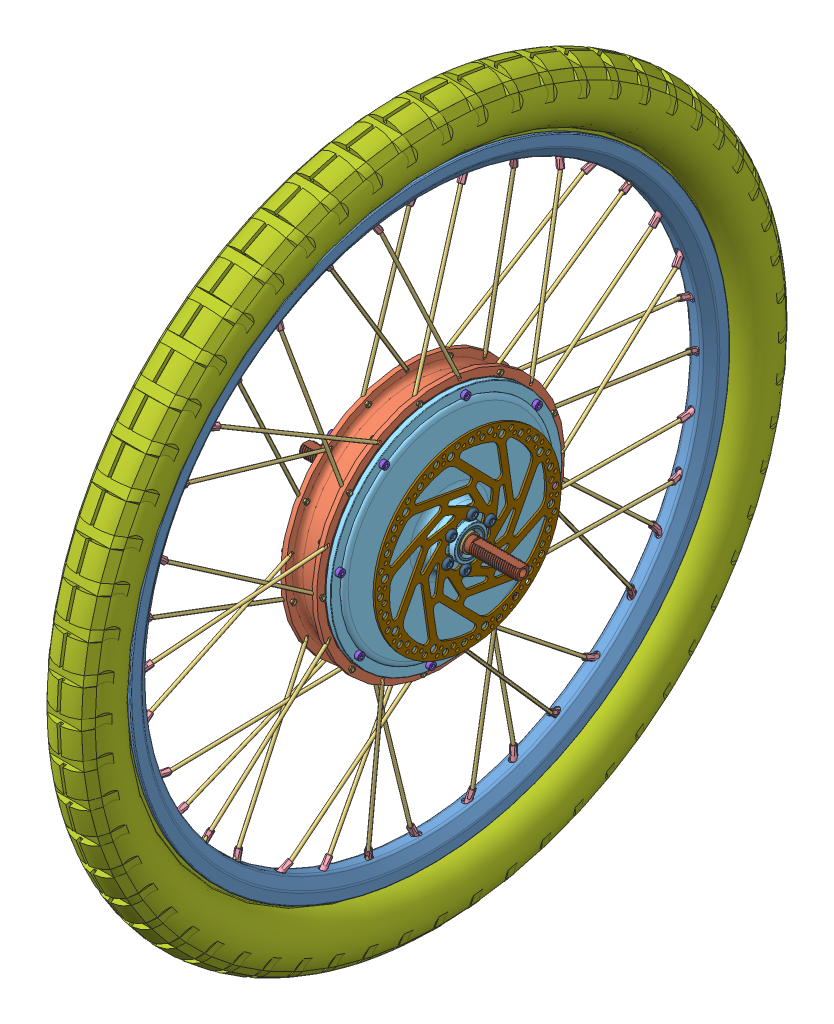
SolidWorks assembly .Rear Wheel eMotor 600W, configuration По умолчанию. Lengths in mm.
Overall size (210 693.38 693.38).
109 component instances, 14 part files, 51 mates.
Components (placement in the parent):
- 26inch rim Vbrake type pistonedHoles-1: .26inch rim Vbrake type pistonedHoles [Default] at (-182.592 -9.6101 580) size (25 580 580)
- 1-Motor Rotor-2: .1-Motor Rotor [По умолчанию] at (-160.092 -9.6101 580) x (0 0.158861 0.987301) z (-1 0 0) size (240 240 36)
- Spoke D3x160-1: .Spoke D3x160 [По умолчанию<Как обработанный>] at (-171.5597 190.5092 596.4307) x (-0.122581 0.920198 0.371764) z (0 -0.374589 0.927191) size (185.5 8.8 5)
- Nut Spokes-1: .Nut Spokes [По умолчанию] at (-182.592 259.5564 627.4613) x (0.418711 0.580778 -0.698124) z (0.230429 -0.811546 -0.536932) size (9 9 15)
- Spoke D3x160-2: .Spoke D3x160 [По умолчанию<Как обработанный>] at (-173.7181 188.552 565.6467) x (-0.0986 0.915447 -0.390174) z (0 -0.392084 -0.919929) size (185.5 8.8 5)
- Nut Spokes-64: .Nut Spokes [По умолчанию] at (-182.592 259.7657 532.5018) x (0.529386 -0.384429 -0.756283) z (0.169202 -0.825691 0.538149) size (9 9 15)
- Spoke D3x160-3: .Spoke D3x160 [По умолчанию<Как обработанный>] at (-186.5307 184.5302 630.8194) x (0.043763 0.847529 0.528941) z (0 -0.529449 0.848342) size (185.5 8.8 5)
- Nut Spokes-65: .Nut Spokes [По умолчанию] at (-182.592 247.5493 673.5984) x (0.485279 0.569067 -0.663828) z (-0.083126 -0.72575 -0.682918) size (9 9 15)
- Spoke D3x160-4: .Spoke D3x160 [По умолчанию<Как обработанный>] at (-188.7293 189.0251 600.1922) x (0.068192 0.972118 -0.224358) z (0 -0.224882 -0.974386) size (185.5 8.8 5)
- Nut Spokes-66: .Nut Spokes [По умолчанию] at (-182.592 263.92 580) x (0.504642 -0.40671 -0.761527) z (-0.122533 -0.906895 0.403147) size (9 9 15)
- Nut Spokes-67: .Nut Spokes [По умолчанию] at (-182.592 166.2124 370.4629) x (0.529386 -0.78062 -0.33224) z (0.169202 -0.2866 0.94299) size (9 9 15)
- Nut Spokes-68: .Nut Spokes [По умолчанию] at (-182.592 -9.6101 306.4687) x (0.529386 -0.811549 0.247262) z (0.169202 0.386594 0.906596) size (9 9 15)
- Nut Spokes-69: .Nut Spokes [По умолчанию] at (-182.592 -185.4326 370.4629) x (0.529386 -0.462746 0.711067) z (0.169202 0.878897 0.445995) size (9 9 15)
- Nut Spokes-70: .Nut Spokes [По умолчанию] at (-182.592 -278.9859 532.5018) x (0.529386 0.102581 0.842157) z (0.169202 0.959954 -0.223292) size (9 9 15)
- Nut Spokes-71: .Nut Spokes [По умолчанию] at (-182.592 -246.4952 716.7657) x (0.529386 0.61991 0.579191) z (0.169202 0.591838 -0.788098) size (9 9 15)
- Nut Spokes-72: .Nut Spokes [По умолчанию] at (-182.592 -103.1633 837.0354) x (0.529386 0.847175 0.045216) z (0.169202 -0.053205 -0.984144) size (9 9 15)
- Nut Spokes-73: .Nut Spokes [По умолчанию] at (-182.592 83.9431 837.0354) x (0.529386 0.678038 -0.509916) z (0.169202 -0.673353 -0.719698) size (9 9 15)
- Nut Spokes-74: .Nut Spokes [По умолчанию] at (-182.592 227.275 716.7657) x (0.529386 0.19164 -0.826453) z (0.169202 -0.978432 -0.118498) size (9 9 15)
- Spoke D3x160-5: .Spoke D3x160 [По умолчанию<Как обработанный>] at (-173.7181 132.9648 441.6286) x (-0.0986 0.450474 -0.887328) z (0 -0.891673 -0.45268) size (185.5 8.8 5)
- Spoke D3x160-6: .Spoke D3x160 [По умолчанию<Как обработанный>] at (-173.7181 10.6652 382.356) x (-0.0986 -0.225281 -0.969292) z (0 -0.974038 0.226384) size (185.5 8.8 5)
- Spoke D3x160-7: .Spoke D3x160 [По умолчанию<Как обработанный>] at (-173.7181 -121.1215 415.5632) x (-0.0986 -0.795624 -0.597713) z (0 -0.60064 0.79952) size (185.5 8.8 5)
- Spoke D3x160-8: .Spoke D3x160 [По умолчанию<Как обработанный>] at (-173.7181 -200.7307 525.7122) x (-0.0986 -0.993686 0.053542) z (0 0.053805 0.998551) size (185.5 8.8 5)
- Spoke D3x160-9: .Spoke D3x160 [По умолчанию<Как обработанный>] at (-173.7181 -190.9125 661.2631) x (-0.0986 -0.726791 0.679745) z (0 0.683073 0.73035) size (185.5 8.8 5)
- Spoke D3x160-10: .Spoke D3x160 [По умолчанию<Как обработанный>] at (-173.7181 -96.2608 758.7901) x (-0.0986 -0.119823 0.987887) z (0 0.992724 0.120409) size (185.5 8.8 5)
- Spoke D3x160-11: .Spoke D3x160 [По умолчанию<Как обработанный>] at (-173.7181 38.9356 772.6592) x (-0.0986 0.543212 0.833786) z (0 0.837869 -0.545872) size (185.5 8.8 5)
- Spoke D3x160-12: .Spoke D3x160 [По умолчанию<Как обработанный>] at (-173.7181 151.417 696.3809) x (-0.0986 0.952072 0.289547) z (0 0.290965 -0.956734) size (185.5 8.8 5)
- Nut Spokes-75: .Nut Spokes [По умолчанию] at (-182.592 227.0909 443.3406) x (0.418711 -0.003844 -0.908111) z (0.230429 -0.966813 0.110338) size (9 9 15)
- Nut Spokes-76: .Nut Spokes [По умолчанию] at (-182.592 83.8704 323.1643) x (0.418711 -0.586667 -0.693183) z (0.230429 -0.669698 0.705979) size (9 9 15)
- Nut Spokes-77: .Nut Spokes [По умолчанию] at (-182.592 -103.0906 323.1643) x (0.418711 -0.894983 -0.153907) z (0.230429 -0.059224 0.971285) size (9 9 15)
- Nut Spokes-78: .Nut Spokes [По умолчанию] at (-182.592 -246.3111 443.3406) x (0.418711 -0.784526 0.457384) z (0.230429 0.578962 0.782116) size (9 9 15)
- Nut Spokes-79: .Nut Spokes [По умолчанию] at (-182.592 -278.7766 627.4613) x (0.418711 -0.306981 0.85466) z (0.230429 0.946245 0.226986) size (9 9 15)
- Nut Spokes-80: .Nut Spokes [По умолчанию] at (-182.592 -185.2961 789.3744) x (0.418711 0.314204 0.852031) z (0.230429 0.87077 -0.434353) size (9 9 15)
- Nut Spokes-81: .Nut Spokes [По умолчанию] at (-182.592 -9.6101 853.3188) x (0.418711 0.788369 0.450727) z (0.230429 0.387851 -0.892454) size (9 9 15)
- Nut Spokes-82: .Nut Spokes [По умолчанию] at (-182.592 166.0758 789.3744) x (0.418711 0.893648 -0.161477) z (0.230429 -0.276547 -0.932965) size (9 9 15)
- Spoke D3x160-13: .Spoke D3x160 [По умолчанию<Как обработанный>] at (-171.5597 154.2516 463.9524) x (-0.122581 0.943878 -0.306704) z (0 0.309035 0.951051) size (185.5 8.8 5)
- Spoke D3x160-14: .Spoke D3x160 [По умолчанию<Как обработанный>] at (-171.5597 41.3213 385.7741) x (-0.122581 0.525907 -0.841662) z (0 0.848058 0.529903) size (185.5 8.8 5)
- Spoke D3x160-15: .Spoke D3x160 [По умолчанию<Как обработанный>] at (-171.5597 -95.4404 398.4762) x (-0.122581 -0.138142 -0.982797) z (0 0.990265 -0.139192) size (185.5 8.8 5)
- Spoke D3x160-16: .Spoke D3x160 [По умолчанию<Как обработанный>] at (-171.5597 -192.0411 496.1154) x (-0.122581 -0.737553 -0.66407) z (0 0.669117 -0.743157) size (185.5 8.8 5)
- Spoke D3x160-17: .Spoke D3x160 [По умолчанию<Как обработанный>] at (-171.5597 -203.2804 633.005) x (-0.122581 -0.991855 -0.034618) z (0 0.034881 -0.999391) size (185.5 8.8 5)
- Spoke D3x160-18: .Spoke D3x160 [По умолчанию<Как обработанный>] at (-171.5597 -123.8992 745.0931) x (-0.122581 -0.782056 0.611033) z (0 -0.615676 -0.787999) size (185.5 8.8 5)
- Spoke D3x160-19: .Spoke D3x160 [По умолчанию<Как обработанный>] at (-171.5597 8.9592 779.9322) x (-0.122581 -0.206325 0.970775) z (0 -0.978152 -0.207893) size (185.5 8.8 5)
- Spoke D3x160-20: .Spoke D3x160 [По умолчанию<Как обработанный>] at (-171.5597 133.1287 721.2209) x (-0.122581 0.465948 0.87628) z (0 -0.882939 0.469488) size (185.5 8.8 5)
- Nut Spokes-83: .Nut Spokes [По умолчанию] at (-182.592 247.5493 486.4016) x (0.485279 0.00923 -0.874311) z (-0.083126 -0.994928 -0.056642) size (9 9 15)
- Nut Spokes-84: .Nut Spokes [По умолчанию] at (-182.592 127.2216 343.0006) x (0.485279 -0.554925 -0.675694) z (-0.083126 -0.798568 0.596137) size (9 9 15)
- Nut Spokes-85: .Nut Spokes [По умолчанию] at (-182.592 -57.1312 310.4942) x (0.485279 -0.859425 -0.160912) z (-0.083126 -0.228549 0.969977) size (9 9 15)
- Nut Spokes-86: .Nut Spokes [По умолчанию] at (-182.592 -219.2484 404.0926) x (0.485279 -0.761791 0.429162) z (-0.083126 0.448411 0.889954) size (9 9 15)
- Nut Spokes-87: .Nut Spokes [По умолчанию] at (-182.592 -283.2734 580) x (0.485279 -0.307705 0.818427) z (-0.083126 0.915554 0.393511) size (9 9 15)
- Nut Spokes-88: .Nut Spokes [По умолчанию] at (-182.592 -219.2484 755.9074) x (0.485279 0.290358 0.82474) z (-0.083126 0.954299 -0.28706) size (9 9 15)
- Nut Spokes-89: .Nut Spokes [По умолчанию] at (-182.592 -57.1312 849.5058) x (0.485279 0.75256 0.445149) z (-0.083126 0.546517 -0.833312) size (9 9 15)
- Nut Spokes-90: .Nut Spokes [По умолчанию] at (-182.592 127.2216 816.9994) x (0.485279 0.862631 -0.142733) z (-0.083126 -0.116986 -0.989649) size (9 9 15)
- Spoke D3x160-21: .Spoke D3x160 [По умолчанию<Как обработанный>] at (-186.5307 171.7761 494.1389) x (0.043763 0.989242 -0.139589) z (0 0.139722 0.990191) size (185.5 8.8 5)
- Spoke D3x160-22: .Spoke D3x160 [По умолчанию<Как обработанный>] at (-186.5307 74.1493 397.6338) x (0.043763 0.668078 -0.742804) z (0 0.743516 0.668718) size (185.5 8.8 5)
- Spoke D3x160-23: .Spoke D3x160 [По умолчанию<Как обработанный>] at (-186.5307 -62.6694 386.4599) x (0.043763 0.034312 -0.998453) z (0 0.99941 0.034345) size (185.5 8.8 5)
- Spoke D3x160-24: .Spoke D3x160 [По умолчанию<Как обработанный>] at (-186.5307 -174.6611 465.8455) x (0.043763 -0.615508 -0.786914) z (0 0.787669 -0.616099) size (185.5 8.8 5)
- Spoke D3x160-25: .Spoke D3x160 [По умолчанию<Как обработанный>] at (-186.5307 -209.4236 598.6453) x (0.043763 -0.977326 -0.20717) z (0 0.207369 -0.978263) size (185.5 8.8 5)
- Spoke D3x160-26: .Spoke D3x160 [По умолчанию<Как обработанный>] at (-186.5307 -150.6911 722.7208) x (0.043763 -0.881841 0.469511) z (0 -0.469961 -0.882687) size (185.5 8.8 5)
- Spoke D3x160-27: .Spoke D3x160 [По умолчанию<Как обработанный>] at (-186.5307 -25.9453 780.0156) x (0.043763 -0.373734 0.926503) z (0 -0.927392 -0.374092) size (185.5 8.8 5)
- Spoke D3x160-28: .Spoke D3x160 [По умолчанию<Как обработанный>] at (-186.5307 106.444 743.7209) x (0.043763 0.309248 0.949974) z (0 -0.950885 0.309545) size (185.5 8.8 5)
- Nut Spokes-91: .Nut Spokes [По умолчанию] at (-182.592 199.9261 404.1782) x (0.504642 -0.801058 -0.321936) z (-0.122533 -0.435584 0.891769) size (9 9 15)
- Nut Spokes-92: .Nut Spokes [По умолчанию] at (-182.592 37.8879 310.6254) x (0.504642 -0.820582 0.268293) z (-0.122533 0.239542 0.963123) size (9 9 15)
- Nut Spokes-93: .Nut Spokes [По умолчанию] at (-182.592 -146.3752 343.1159) x (0.504642 -0.456147 0.732984) z (-0.122533 0.802583 0.58382) size (9 9 15)
- Nut Spokes-94: .Nut Spokes [По умолчанию] at (-182.592 -266.6444 486.4472) x (0.504642 0.121724 0.854704) z (-0.122533 0.990087 -0.068658) size (9 9 15)
- Nut Spokes-95: .Nut Spokes [По умолчанию] at (-182.592 -266.6444 673.5528) x (0.504642 0.64264 0.576499) z (-0.122533 0.714318 -0.689011) size (9 9 15)
- Nut Spokes-96: .Nut Spokes [По умолчанию] at (-182.592 -146.3752 816.8841) x (0.504642 0.862857 0.028543) z (-0.122533 0.104312 -0.986967) size (9 9 15)
- Nut Spokes-97: .Nut Spokes [По умолчанию] at (-182.592 37.8879 849.3746) x (0.504642 0.679333 -0.532769) z (-0.122533 -0.554503 -0.823111) size (9 9 15)
- Nut Spokes-98: .Nut Spokes [По умолчанию] at (-182.592 199.9261 755.8218) x (0.504642 0.177943 -0.844791) z (-0.122533 -0.95386 -0.274112) size (9 9 15)
- Spoke D3x160-29: .Spoke D3x160 [По умолчанию<Как обработанный>] at (-188.7293 155.5326 467.7879) x (0.068192 0.600471 -0.796734) z (0 -0.798593 -0.601872) size (185.5 8.8 5)
- Spoke D3x160-30: .Spoke D3x160 [По умолчанию<Как обработанный>] at (-188.7293 44.768 387.8889) x (0.068192 -0.052143 -0.996309) z (0 -0.998633 0.052265) size (185.5 8.8 5)
- Spoke D3x160-31: .Spoke D3x160 [По умолчанию<Как обработанный>] at (-188.7293 -91.4407 397.8808) x (0.068192 -0.680359 -0.7297) z (0 -0.731402 0.681946) size (185.5 8.8 5)
- Spoke D3x160-32: .Spoke D3x160 [По умолчанию<Как обработанный>] at (-188.7293 -189.36 493.0883) x (0.068192 -0.990227 -0.121656) z (0 -0.12194 0.992537) size (185.5 8.8 5)
- Spoke D3x160-33: .Spoke D3x160 [По умолчанию<Как обработанный>] at (-188.7293 -203.1723 628.9627) x (0.068192 -0.836757 0.543312) z (0 0.544579 0.838709) size (185.5 8.8 5)
- Spoke D3x160-34: .Spoke D3x160 [По умолчанию<Как обработанный>] at (-188.7293 -126.4147 741.927) x (0.068192 -0.291759 0.954058) z (0 0.956284 0.29244) size (185.5 8.8 5)
- Spoke D3x160-35: .Spoke D3x160 [По умолчанию<Как обработанный>] at (-188.7293 4.9971 779.1238) x (0.068192 0.389756 0.91839) z (0 0.920533 -0.390666) size (185.5 8.8 5)
- Spoke D3x160-36: .Spoke D3x160 [По умолчанию<Как обработанный>] at (-188.7293 129.574 723.1484) x (0.068192 0.8889 0.452997) z (0 0.454054 -0.890974) size (185.5 8.8 5)
- 2-Motor Shield RotorBrakeSide-1: .2-Motor Shield RotorBrakeSide [По умолчанию] at (-159.592 -9.6101 580) x (0 -0.158861 -0.987301) z (1 0 0) size (224 224 29)
- 2-Motor Shield Rear Wheel RigtSide Cassette-1: .2-Motor Shield Rear Wheel RigtSide Cassette [По умолчанию] at (-195.592 -9.6101 580) x (0 0.810459 0.585795) z (-1 0 0) size (224 224 41)
- Wheel Gum-1: .Wheel Gum [По умолчанию] at (-183.092 -9.6101 580) size (55 693.38 693.38)
- M4x10 8.8-1: .M4x10 8.8 [По умолчанию] at (-204.492 7.2292 684.6539) x (0 0.438024 -0.898963) z (1 0 0) size (6.9 6.9 14.35)
- M4x10 8.8-2: .M4x10 8.8 [По умолчанию] at (-204.492 76.2985 642.0943) x (0 -0.325933 -0.945393) z (1 0 0) size (6.9 6.9 14.35)
- M4x10 8.8-3: .M4x10 8.8 [По умолчанию] at (-204.492 95.0438 563.1607) x (0 -0.898963 -0.438024) z (1 0 0) size (6.9 6.9 14.35)
- M4x10 8.8-4: .M4x10 8.8 [По умолчанию] at (-204.492 52.4842 494.0914) x (0 -0.945393 0.325933) z (1 0 0) size (6.9 6.9 14.35)
- M4x10 8.8-5: .M4x10 8.8 [По умолчанию] at (-204.492 -26.4494 475.3461) x (0 -0.438024 0.898963) z (1 0 0) size (6.9 6.9 14.35)
- M4x10 8.8-6: .M4x10 8.8 [По умолчанию] at (-204.492 -95.5188 517.9057) x (0 0.325933 0.945393) z (1 0 0) size (6.9 6.9 14.35)
- M4x10 8.8-7: .M4x10 8.8 [По умолчанию] at (-204.492 -114.264 596.8393) x (0 0.898963 0.438024) z (1 0 0) size (6.9 6.9 14.35)
- M4x10 8.8-8: .M4x10 8.8 [По умолчанию] at (-204.492 -71.7044 665.9086) x (0 0.945393 -0.325933) z (1 0 0) size (6.9 6.9 14.35)
- M4x10 8.8-9: .M4x10 8.8 [По умолчанию] at (-150.692 -95.5188 517.9057) x (0 0.110879 0.993834) z (-1 0 0) size (6.9 6.9 14.35)
- M4x10 8.8-10: .M4x10 8.8 [По умолчанию] at (-150.692 -26.4494 475.3461) x (0 -0.624343 0.78115) z (-1 0 0) size (6.9 6.9 14.35)
- M4x10 8.8-11: .M4x10 8.8 [По умолчанию] at (-150.692 52.4842 494.0914) x (0 -0.993834 0.110879) z (-1 0 0) size (6.9 6.9 14.35)
- M4x10 8.8-12: .M4x10 8.8 [По умолчанию] at (-150.692 95.0438 563.1607) x (0 -0.78115 -0.624343) z (-1 0 0) size (6.9 6.9 14.35)
- M4x10 8.8-13: .M4x10 8.8 [По умолчанию] at (-150.692 76.2985 642.0943) x (0 -0.110879 -0.993834) z (-1 0 0) size (6.9 6.9 14.35)
- M4x10 8.8-14: .M4x10 8.8 [По умолчанию] at (-150.692 7.2292 684.6539) x (0 0.624343 -0.78115) z (-1 0 0) size (6.9 6.9 14.35)
- M4x10 8.8-15: .M4x10 8.8 [По умолчанию] at (-150.692 -71.7044 665.9086) x (0 0.993834 -0.110879) z (-1 0 0) size (6.9 6.9 14.35)
- M4x10 8.8-16: .M4x10 8.8 [По умолчанию] at (-150.692 -114.264 596.8393) x (0 0.78115 0.624343) z (-1 0 0) size (6.9 6.9 14.35)
- Rotor Disk Brake 180mm-1: .Rotor Disk Brake 180mm [Default] at (-133.692 -9.6101 580) x (0 0.631228 0.775597) z (-1 0 0) size (180 180 1.9)
- M6x20 8.8 rounded head-1: .M6x20 8.8 rounded head [По умолчанию] at (-130.692 4.2769 597.0631) x (0 0 1) z (-1 0 0) size (9.9 9.9 23.58)
- M6x20 8.8 rounded head-2: .M6x20 8.8 rounded head [По умолчанию] at (-130.692 -17.4437 600.5581) x (0 -0.866025 0.5) z (-1 0 0) size (9.9 9.9 23.58)
- M6x20 8.8 rounded head-3: .M6x20 8.8 rounded head [По умолчанию] at (-130.692 -31.3307 583.4949) x (0 -0.866025 -0.5) z (-1 0 0) size (9.9 9.9 23.58)
- M6x20 8.8 rounded head-4: .M6x20 8.8 rounded head [По умолчанию] at (-130.692 -23.4971 562.9369) x (0 0 -1) z (-1 0 0) size (9.9 9.9 23.58)
- M6x20 8.8 rounded head-5: .M6x20 8.8 rounded head [По умолчанию] at (-130.692 -1.7765 559.4419) x (0 0.866025 -0.5) z (-1 0 0) size (9.9 9.9 23.58)
- M6x20 8.8 rounded head-6: .M6x20 8.8 rounded head [По умолчанию] at (-130.692 12.1105 576.5051) x (0 0.866025 0.5) z (-1 0 0) size (9.9 9.9 23.58)
- shaft rear 14mm-1: .shaft rear 14mm [По умолчанию] at (-80.592 -9.6101 580) x (0 0.052208 0.998636) z (-1 0 0) size (16.17 14 210)
- 26x14x8 rolled-1: .26x14x8 rolled [По умолчанию] at (-151.592 -8.9482 574.9476) x (0 0.494808 -0.869002) z (1 0 0) size (28.13 28.13 8)
  - InnerCage-1: .InnerCage [По умолчанию] at (-4.7181 1.9248 13) size (17 17 8)
  - roll 3mm-1: .roll 3mm [По умолчанию] at (-14.7166 2.0947 13.75) size (3 3 6.5)
  - Outter Cage-1: .Outter Cage [По умолчанию] at (-4.7181 1.9248 13) x (0.085785 -0.996314 0) z (0 0 1) size (26 26 8)
- 26x14x8 rolled-2: .26x14x8 rolled [По умолчанию] at (-249.592 -11.5349 575.2819) x (0 0 -1) z (1 0 0) size (28.13 28.13 8)
  - InnerCage-1: .InnerCage [По умолчанию] at (-4.7181 1.9248 13) size (17 17 8)
  - roll 3mm-1: .roll 3mm [По умолчанию] at (-14.7166 2.0947 13.75) size (3 3 6.5)
  - Outter Cage-1: .Outter Cage [По умолчанию] at (-4.7181 1.9248 13) x (0.085785 -0.996314 0) z (0 0 1) size (26 26 8)
Mates (geometry in assembly coordinates):
- Расстояние1: distance = 0 mm aligned: plane of 1-Motor Rotor-2 through (-195.092 -9.6101 580) normal (-1 0 0); plane of 26inch rim Vbrake type pistonedHoles-1 through (-195.092 -298.6101 580) normal (-1 0 0)
- Концентричный1: concentric anti-aligned: cylinder of 26inch rim Vbrake type pistonedHoles-1 through (-198.7674 -9.6101 580) axis (-1 0 0) radius 269; cylinder of 1-Motor Rotor-2 through (-160.092 -9.6101 580) axis (1 0 0) radius 108
- Совпадение1: coincident: line of assembly; point of Spoke D3x160-1; line of 26inch rim Vbrake type pistonedHoles-1 through (-182.592 275.9841 630.358) axis (0 -0.984808 -0.173648)
- Совпадение2: coincident: line of assembly; point of 1-Motor Rotor-2; line of Spoke D3x160-1 through (-160.5274 107.6913 562.9719) axis (-0.122581 0.920198 0.371764)
- Совпадение3: coincident: line of assembly; point of 1-Motor Rotor-2; line of Spoke D3x160-1 through (-163.137 104.5898 561.7189) axis (-0.992458 -0.113656 -0.045918)
- Совпадение4: coincident: line of Spoke D3x160-1 through (-160.5274 107.6913 562.9719) axis (-0.122581 0.920198 0.371764)
- Совпадение5: coincident: line of 26inch rim Vbrake type pistonedHoles-1 through (-182.592 275.9841 630.358) axis (0 -0.984808 -0.173648)
- Совпадение6: coincident: line of Spoke D3x160-1 through (-160.5274 107.6913 562.9719) axis (-0.122581 0.920198 0.371764)
- Совпадение7: coincident: line of 26inch rim Vbrake type pistonedHoles-1 through (-182.592 275.9841 630.358) axis (0 -0.984808 -0.173648)
- Расстояние3: distance = 9 mm: cylinder of assembly; point of Nut Spokes-1; cylinder of 26inch rim Vbrake type pistonedHoles-1 through (-198.7674 -9.6101 580) axis (-1 0 0) radius 269
- Совпадение9: coincident: line of 26inch rim Vbrake type pistonedHoles-1 through (-182.592 275.9841 529.642) axis (0 -0.984808 0.173648)
- Совпадение11: coincident: line of assembly; point of 1-Motor Rotor-2; line of Spoke D3x160-2 through (-164.8441 106.1618 600.7624) axis (-0.0986 0.915447 -0.390174)
- Совпадение12: coincident: line of assembly; point of 1-Motor Rotor-2; line of Spoke D3x160-2 through (-161.5629 103.6876 601.8169) axis (0.995127 0.090705 -0.038659)
- Совпадение13: coincident: line of 26inch rim Vbrake type pistonedHoles-1 through (-182.592 275.9841 529.642) axis (0 -0.984808 0.173648)
- Совпадение14: coincident: line of Spoke D3x160-2 through (-164.8441 106.1618 600.7624) axis (-0.0986 0.915447 -0.390174)
- Расстояние4: distance = 9 mm: cylinder of assembly; point of Nut Spokes-64; cylinder of 26inch rim Vbrake type pistonedHoles-1 through (-198.7674 -9.6101 580) axis (-1 0 0) radius 269
- Совпадение16: coincident: line of 26inch rim Vbrake type pistonedHoles-1 through (-182.592 262.9008 679.1858) axis (0 -0.939693 -0.34202)
- Совпадение17: coincident: line of assembly; point of 1-Motor Rotor-2; line of Spoke D3x160-3 through (-190.4694 108.2526 583.2146) axis (0.043763 0.847529 0.528941)
- Совпадение18: coincident: line of assembly; point of 1-Motor Rotor-2; line of Spoke D3x160-3 through (-193.5978 105.8214 581.6973) axis (-0.999042 0.037126 0.02317)
- Совпадение19: coincident: line of 26inch rim Vbrake type pistonedHoles-1 through (-182.592 262.9008 679.1858) axis (0 -0.939693 -0.34202)
- Совпадение20: coincident: line of Spoke D3x160-3 through (-190.4694 108.2526 583.2146) axis (0.043763 0.847529 0.528941)
- Расстояние5: distance = 9 mm: cylinder of assembly; point of Nut Spokes-65; cylinder of 26inch rim Vbrake type pistonedHoles-1 through (-198.7674 -9.6101 580) axis (-1 0 0) radius 269
- Совпадение21: coincident: line of 26inch rim Vbrake type pistonedHoles-1 through (-182.592 280.3899 580) axis (0 -1 0)
- Совпадение22: coincident: line of assembly; point of 1-Motor Rotor-2; line of Spoke D3x160-4 through (-194.8665 101.5345 620.3845) axis (0.068192 0.972118 -0.224358)
- Совпадение23: coincident: line of assembly; point of 1-Motor Rotor-2; line of Spoke D3x160-4 through (-192.0781 98.4188 621.1036) axis (0.997672 -0.066445 0.015335)
- Совпадение24: coincident: line of 26inch rim Vbrake type pistonedHoles-1 through (-182.592 280.3899 580) axis (0 -1 0)
- Совпадение25: coincident: line of Spoke D3x160-4 through (-194.8665 101.5345 620.3845) axis (0.068192 0.972118 -0.224358)
- Расстояние6: distance = 9 mm: cylinder of assembly; point of Nut Spokes-66; cylinder of 26inch rim Vbrake type pistonedHoles-1 through (-198.7674 -9.6101 580) axis (-1 0 0) radius 269
- Расстояние7: distance = 0 mm anti-aligned: plane of 2-Motor Shield RotorBrakeSide-1 through (-159.592 -9.6101 580) normal (-1 0 0); plane of 1-Motor Rotor-2 through (-159.592 -9.6101 580) normal (1 0 0)
- Концентричный3: concentric anti-aligned: cylinder of 1-Motor Rotor-2 through (-159.592 -9.6101 580) axis (-1 0 0) radius 100; cylinder of 2-Motor Shield RotorBrakeSide-1 through (-159.592 -9.6101 580) axis (1 0 0) radius 7.25
- Концентричный4: concentric aligned: cylinder of 1-Motor Rotor-2 through (-165.592 52.4842 494.0914) axis (1 0 0) radius 1.6; circle of 2-Motor Shield RotorBrakeSide-1
- Концентричный5: concentric aligned: cylinder of 1-Motor Rotor-2 through (-159.592 -9.6101 580) axis (-1 0 0) radius 100; cylinder of 2-Motor Shield Rear Wheel RigtSide Cassette-1 through (-195.592 -9.6101 580) axis (-1 0 0) radius 7.25
- Расстояние8: distance = 0 mm anti-aligned: plane of 2-Motor Shield Rear Wheel RigtSide Cassette-1 through (-195.592 -9.6101 580) normal (1 0 0); plane of 1-Motor Rotor-2 through (-195.592 -9.6101 580) normal (-1 0 0)
- Концентричный6: concentric aligned: circle of 1-Motor Rotor-2; circle of 2-Motor Shield Rear Wheel RigtSide Cassette-1
- Совпадение27: coincident anti-aligned: plane of 26inch rim Vbrake type pistonedHoles-1 through (-191.092 -298.6101 580) normal (1 0 0); plane of Wheel Gum-1 through (-191.092 282.608 580) normal (-1 0 0)
- Концентричный7: concentric aligned: cylinder of 26inch rim Vbrake type pistonedHoles-1 through (-198.7674 -9.6101 580) axis (-1 0 0) radius 282; circle of Wheel Gum-1
- Расстояние9: distance = 0 mm anti-aligned: plane of M4x10 8.8-1 through (-200.592 7.2292 684.6539) normal (1 0 0); plane of 2-Motor Shield Rear Wheel RigtSide Cassette-1 through (-200.592 -9.6101 580) normal (-1 0 0)
- Концентричный8: concentric aligned: circle of 2-Motor Shield Rear Wheel RigtSide Cassette-1; cylinder of M4x10 8.8-1 through (-200.592 7.2292 684.6539) axis (-1 0 0) radius 3.45
- Расстояние10: distance = 0 mm anti-aligned: plane of M4x10 8.8-9 through (-154.592 -95.5188 517.9057) normal (-1 0 0); plane of 2-Motor Shield RotorBrakeSide-1 through (-154.592 -9.6101 580) normal (1 0 0)
- Концентричный9: concentric aligned: circle of 2-Motor Shield RotorBrakeSide-1; cylinder of M4x10 8.8-9 through (-154.592 -95.5188 517.9057) axis (1 0 0) radius 3.45
- Расстояние11: distance = 1 mm anti-aligned: plane of 2-Motor Shield RotorBrakeSide-1 through (-136.592 -9.6101 580) normal (1 0 0); plane of Rotor Disk Brake 180mm-1 through (-135.592 -9.6101 580) normal (-1 0 0)
- Концентричный10: concentric anti-aligned: cylinder of 2-Motor Shield RotorBrakeSide-1 through (-159.592 -9.6101 580) axis (1 0 0) radius 7.25; circle of Rotor Disk Brake 180mm-1
- Концентричный11: concentric aligned: circle of 2-Motor Shield RotorBrakeSide-1; circle of Rotor Disk Brake 180mm-1
- Расстояние12: distance = 0 mm anti-aligned: plane of M6x20 8.8 rounded head-1 through (-133.692 4.2769 597.0631) normal (-1 0 0); plane of Rotor Disk Brake 180mm-1 through (-133.692 -9.6101 580) normal (1 0 0)
- Концентричный12: concentric aligned: circle of Rotor Disk Brake 180mm-1; cylinder of M6x20 8.8 rounded head-1 through (-133.692 4.2769 597.0631) axis (1 0 0) radius 4.95
- Концентричный13: concentric aligned: cylinder of 2-Motor Shield RotorBrakeSide-1 through (-159.592 -9.6101 580) axis (1 0 0) radius 7.25; cylinder of shaft rear 14mm-1 through (-290.592 -9.6101 580) axis (1 0 0) radius 7
- Расстояние13: distance = 50 mm aligned: plane of 2-Motor Shield RotorBrakeSide-1 through (-130.592 -9.6101 580) normal (1 0 0); plane of shaft rear 14mm-1 through (-80.592 -9.6101 580) normal (1 0 0)
- Концентричный14: concentric aligned: cylinder of 2-Motor Shield RotorBrakeSide-1 through (-130.592 -9.6101 580) axis (-1 0 0) radius 13; cylinder of 26x14x8 rolled-1/Outter Cage-1 through (-130.592 -9.6101 580) axis (-1 0 0) radius 13
- Совпадение30: coincident anti-aligned: plane of 2-Motor Shield RotorBrakeSide-1 through (-138.592 -9.6101 580) normal (1 0 0); plane of 26x14x8 rolled-1/Outter Cage-1 through (-138.592 -9.6101 580) normal (-1 0 0)
- Совпадение32: coincident aligned: plane of 2-Motor Shield Rear Wheel RigtSide Cassette-1 through (-236.592 -9.6101 580) normal (-1 0 0); plane of 26x14x8 rolled-2/Outter Cage-1 through (-236.592 -9.6101 580) normal (-1 0 0)
- Концентричный15: concentric anti-aligned: cylinder of 2-Motor Shield Rear Wheel RigtSide Cassette-1 through (-236.592 -9.6101 580) axis (1 0 0) radius 13; cylinder of 26x14x8 rolled-2/InnerCage-1 through (-228.592 -9.6101 580) axis (-1 0 0) radius 7
